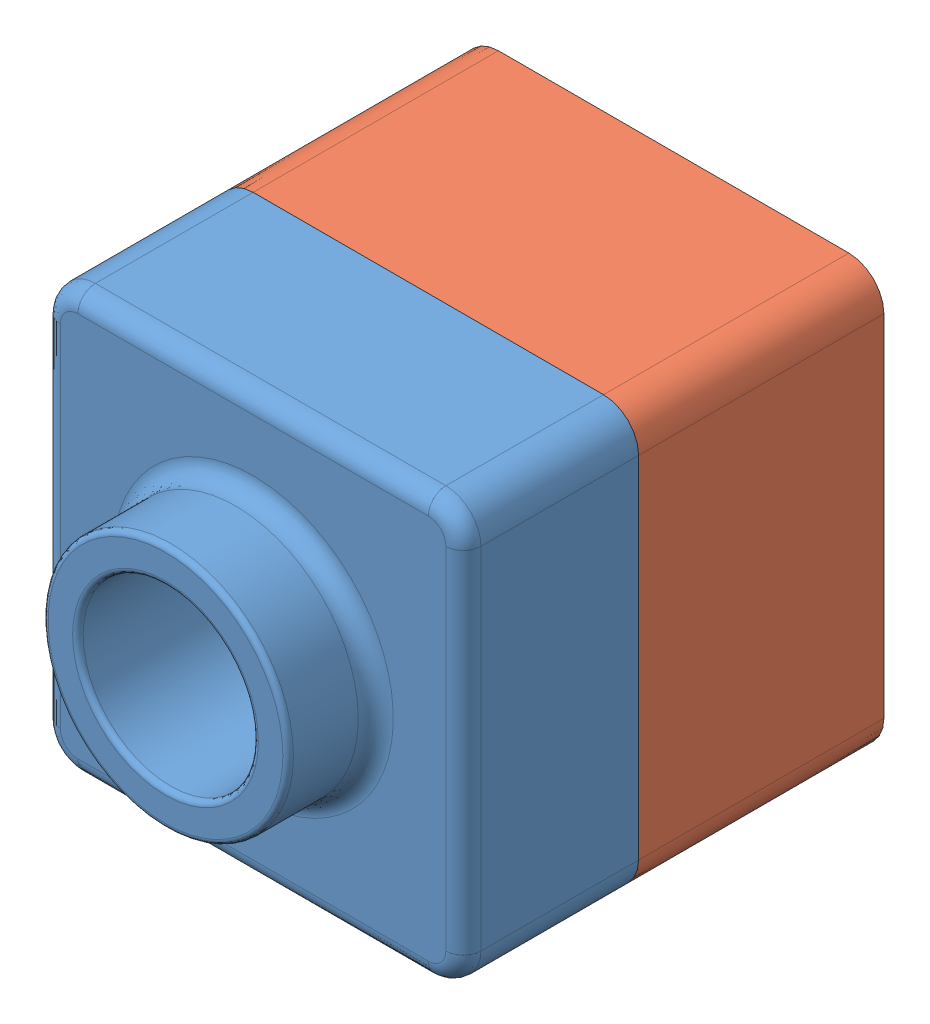
SolidWorks assembly Assembly of lesson 1 and 2, configuration Default. Lengths in mm.
Overall size (120 120 145).
2 component instances, 2 part files, 3 mates.
Components (placement in the parent):
- Lesson1Parts-1: Lesson1Parts [Default] at (-25.0892 -4.052 64.3594) size (120 120 75)
- Lesson2Assemblies-1: Lesson2Assemblies [Default] at (-25.0892 -4.052 -5.6406) size (120 120 90)
Mates (geometry in assembly coordinates):
- Coincident1: coincident anti-aligned: plane of Lesson1Parts-1 through (-25.0892 113.948 114.3594) normal (0 -1 0); plane of Lesson2Assemblies-1 through (84.9108 113.948 64.3594) normal (0 1 0)
- Coincident2: coincident: line of Lesson1Parts-1 through (84.9108 115.948 64.3594) axis (-1 0 0); plane of Lesson2Assemblies-1 through (-15.0892 105.948 64.3594) normal (0 0 1)
- Coincident3: coincident aligned: plane of Lesson1Parts-1 through (-25.0892 -4.052 114.3594) normal (-1 0 0); plane of Lesson2Assemblies-1 through (-25.0892 -4.052 84.3594) normal (-1 0 0)
